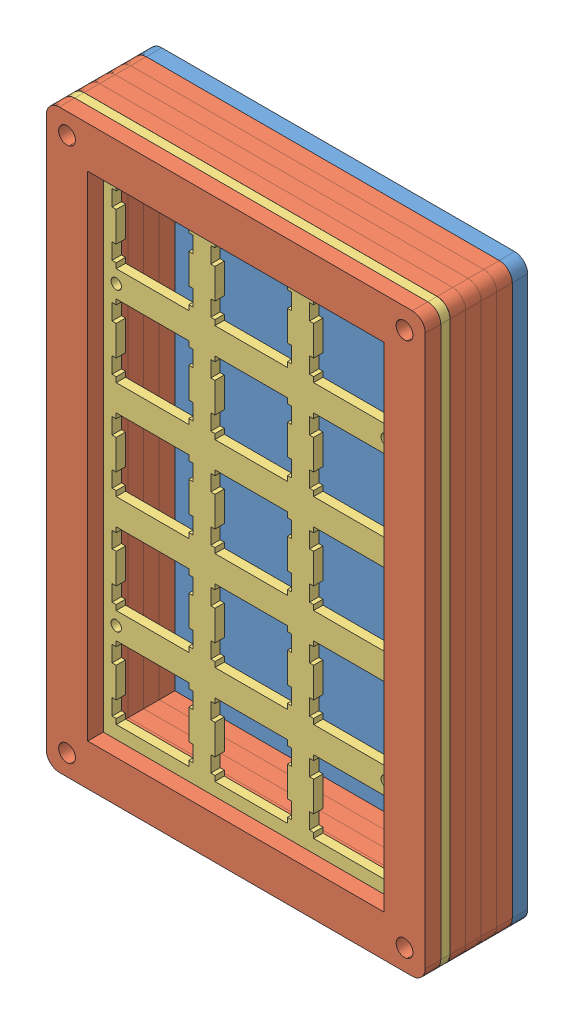
SolidWorks assembly 小键盘组装, configuration 默认. Lengths in mm.
Overall size (73.17 111.26 19.8).
7 component instances, 3 part files, 0 mates.
Components (placement in the parent):
- 数字键盘底层-1: 数字键盘底层 [默认] at origin size (73.15 111.25 3)
- 边框-2: 边框 [默认] at (0 0 3) size (73.15 111.25 3)
- 边框-3: 边框 [默认] at (0 0 6) size (73.15 111.25 3)
- 边框-4: 边框 [默认] at (0 0 9) size (73.15 111.25 3)
- 边框-5: 边框 [默认] at (0 0 12) size (73.15 111.25 3)
- 定位板-1: 定位板 [默认] at (0 0 15) size (73.15 111.25 1.8)
- 边框-7: 边框 [默认] at (0 0 16.8) size (73.15 111.25 3)
